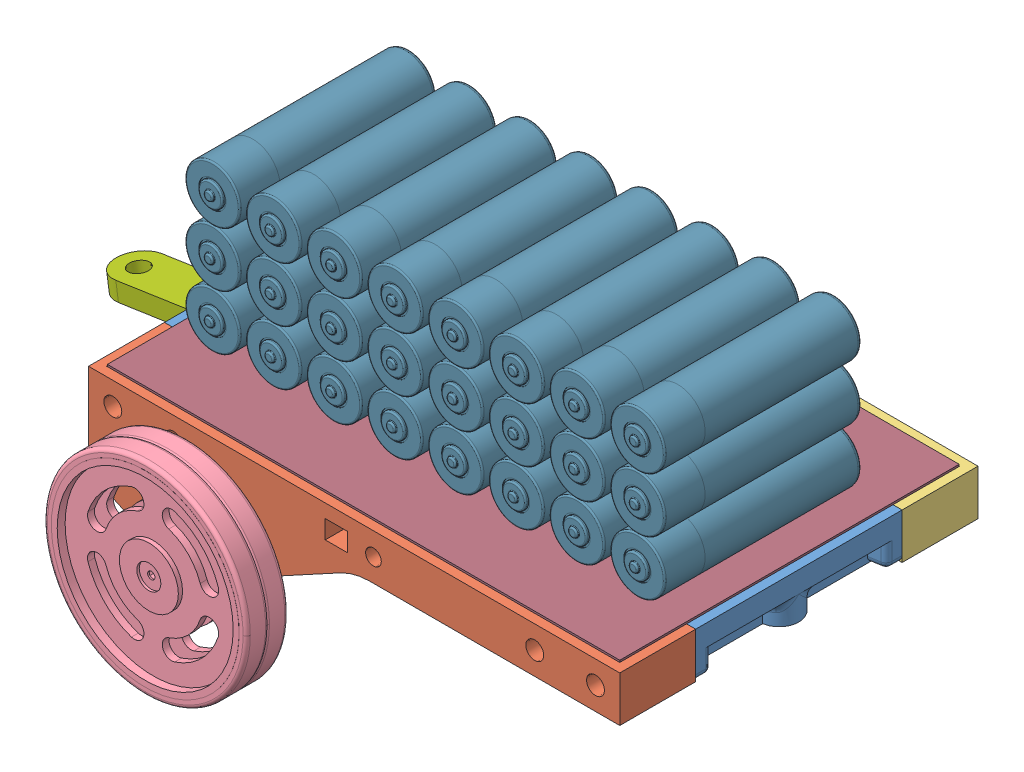
SolidWorks assembly WAGON2, TOP ASSY, configuration Default. Lengths in mm.
Overall size (226.29 129 145.66).
53 component instances, 14 part files, 63 mates.
Components (placement in the parent):
- WAGON2, CHASSIS, TOP-1: WAGON2, CHASSIS, TOP [Default] at (-93.9751 43.1083 20.3022) size (175 15 80.6)
- WAGON2, CHASSIS, SIDE, RIGHT-1: WAGON2, CHASSIS, SIDE, RIGHT [Default] at (-93.9751 38.1083 79.3022) size (175 44 25)
- WAGON2, CHASSIS, SIDE, RIGHT, MIRROR-2: WAGON2, CHASSIS, SIDE, RIGHT, MIRROR [Default] at (-93.9751 38.1083 -38.6978) size (175 44 25)
- WAGON2, WHEEl, GM8-1: WAGON2, WHEEl, GM8 [Default] at (-148.9751 8.1083 83.0868) x (0 0 1) z (-1 0 0) size (7.52 66.8 66.8)
- WAGON2, WHEEl, GM8-2: WAGON2, WHEEl, GM8 [Default] at (-148.9751 8.1083 -42.4824) x (0 0 -1) z (0.999196 -0.040101 0) size (7.52 66.8 66.8)
- WAGON2, REAR HITCH, PIVOT SHAFT, 3MM-1: WAGON2, REAR HITCH, PIVOT SHAFT, 3MM [Default] at (-174.9751 34.2083 20.3022) x (0 0 1) z (-0.598714 0.800963 0) size (28 3 3)
- SENSOR, FSR, INTERLINK 406-1: SENSOR, FSR, INTERLINK 406 [Default] at (-93.9751 44.3383 20.3022) x (0 0 1) z (-1 0 0) size (43.7 18.96 67.12)
- WAGON2, REAR HITCH, PIVOT ARM-1: WAGON2, REAR HITCH, PIVOT ARM [Default] at (-223.7399 22.2437 20.3022) x (0.988941 0.148309 0) z (0 0 1) size (63.2 15.2 15.2)
- SENSOR, BOM, VISHAY TSOP4838-1: SENSOR, BOM, VISHAY TSOP4838 [Default] at (-99.8171 38.1083 -30.6478) x (1 0 0) z (0 0 -1) size (9.49 6 5.4)
- SENSOR, BOM, VISHAY TSOP4838-2: SENSOR, BOM, VISHAY TSOP4838 [Default] at (-99.8171 38.1083 71.2522) size (9.49 6 5.4)
- SENSOR, BOM,TSAL6200-1: SENSOR, BOM,TSAL6200 [Default] at (-87.6251 38.1083 73.2022) x (0.945458 0.325744 0) z (0 0 1) size (5.39 5.8 14.08)
- SENSOR, BOM,TSAL6200-2: SENSOR, BOM,TSAL6200 [Default] at (-87.6251 38.1083 -32.5978) x (0.886273 -0.463163 0) z (0 0 -1) size (5.39 5.8 14.08)
- FASTENER, 4-40 THREAD FORMING, PHILIPS, 0'375IN, 93878A108-1: FASTENER, 4-40 THREAD FORMING, PHILIPS, 0'375IN, 93878A108 [93878A108] at (-173.4751 38.1083 59.3022) size (5.56 5.56 11.45)
- FASTENER, 4-40 THREAD FORMING, PHILIPS, 0'375IN, 93878A108-2: FASTENER, 4-40 THREAD FORMING, PHILIPS, 0'375IN, 93878A108 [93878A108] at (-153.4751 38.1083 59.3022) size (5.56 5.56 11.45)
- FASTENER, 4-40 THREAD FORMING, PHILIPS, 0'375IN, 93878A108-3: FASTENER, 4-40 THREAD FORMING, PHILIPS, 0'375IN, 93878A108 [93878A108] at (-34.4751 38.1083 59.3022) size (5.56 5.56 11.45)
- FASTENER, 4-40 THREAD FORMING, PHILIPS, 0'375IN, 93878A108-4: FASTENER, 4-40 THREAD FORMING, PHILIPS, 0'375IN, 93878A108 [93878A108] at (-14.4751 38.1083 59.3022) size (5.56 5.56 11.45)
- FASTENER, 4-40 THREAD FORMING, PHILIPS, 0'375IN, 93878A108-5: FASTENER, 4-40 THREAD FORMING, PHILIPS, 0'375IN, 93878A108 [93878A108] at (-153.4751 38.1083 -18.6978) x (-0.880957 -0.473196 0) z (0 0 -1) size (5.56 5.56 11.45)
- FASTENER, 4-40 THREAD FORMING, PHILIPS, 0'375IN, 93878A108-6: FASTENER, 4-40 THREAD FORMING, PHILIPS, 0'375IN, 93878A108 [93878A108] at (-173.4751 38.1083 -18.6978) x (-0.880957 -0.473196 0) z (0 0 -1) size (5.56 5.56 11.45)
- FASTENER, 4-40 THREAD FORMING, PHILIPS, 0'375IN, 93878A108-7: FASTENER, 4-40 THREAD FORMING, PHILIPS, 0'375IN, 93878A108 [93878A108] at (-34.4751 38.1083 -18.6978) x (-0.880957 -0.473196 0) z (0 0 -1) size (5.56 5.56 11.45)
- FASTENER, 4-40 THREAD FORMING, PHILIPS, 0'375IN, 93878A108-8: FASTENER, 4-40 THREAD FORMING, PHILIPS, 0'375IN, 93878A108 [93878A108] at (-14.4751 38.1083 -18.6978) x (-0.880957 -0.473196 0) z (0 0 -1) size (5.56 5.56 11.45)
- WAGON2, CHASSIS, PIVOT MOUNT-1: WAGON2, CHASSIS, PIVOT MOUNT [Default] at (-174.9751 31.6083 9.3022) size (13.34 2 6.5)
- WAGON2, CHASSIS, PIVOT MOUNT-2: WAGON2, CHASSIS, PIVOT MOUNT [Default] at (-174.9751 31.6083 31.3022) size (13.34 2 6.5)
- FASTENER, 4-40 THREAD FORMING, PHILIPS, 0'25IN, 93878A106-1: FASTENER, 4-40 THREAD FORMING, PHILIPS, 0'25IN, 93878A106 [93878A106] at (-171.7251 30.6083 31.3022) x (1 0 0) z (0 -1 0) size (5.56 5.56 8.28)
- FASTENER, 4-40 THREAD FORMING, PHILIPS, 0'25IN, 93878A106-2: FASTENER, 4-40 THREAD FORMING, PHILIPS, 0'25IN, 93878A106 [93878A106] at (-178.2251 30.6083 31.3022) x (1 0 0) z (0 -1 0) size (5.56 5.56 8.28)
- FASTENER, 4-40 THREAD FORMING, PHILIPS, 0'25IN, 93878A106-3: FASTENER, 4-40 THREAD FORMING, PHILIPS, 0'25IN, 93878A106 [93878A106] at (-171.7251 30.6083 9.3022) x (1 0 0) z (0 -1 0) size (5.56 5.56 8.28)
- FASTENER, 4-40 THREAD FORMING, PHILIPS, 0'25IN, 93878A106-4: FASTENER, 4-40 THREAD FORMING, PHILIPS, 0'25IN, 93878A106 [93878A106] at (-178.2251 30.6083 9.3022) x (1 0 0) z (0 -1 0) size (5.56 5.56 8.28)
- WAGON2, CHASSIS, TOP, LOAD PLATE-1: WAGON2, CHASSIS, TOP, LOAD PLATE [Default] at (-93.9751 44.5583 20.3022) size (168.8 1.59 111.8)
- WAGON2, WHEEl, GM8-3: WAGON2, WHEEl, GM8 [Default] at (-148.9751 8.1083 89.3987) x (0 0 1) z (-1 0 0) size (7.52 66.8 66.8)
- WAGON2, WHEEl, GM8-4: WAGON2, WHEEl, GM8 [Default] at (-148.9751 8.1083 -48.7943) x (0 0 -1) z (0.999196 -0.040101 0) size (7.52 66.8 66.8)
- BATTERY, UR18650E-1: BATTERY, UR18650E [Default] at (-164.6562 55.1708 -9.3854) x (0.958428 0.285334 0) z (0.285334 -0.958428 0) size (18.05 66.2 18.05)
- BATTERY, UR18650E-2: BATTERY, UR18650E [Default] at (-144.6562 55.1708 -9.3854) x (0.958428 0.285334 0) z (0.285334 -0.958428 0) size (18.05 66.2 18.05)
- BATTERY, UR18650E-3: BATTERY, UR18650E [Default] at (-124.6562 55.1708 -9.3854) x (0.958428 0.285334 0) z (0.285334 -0.958428 0) size (18.05 66.2 18.05)
- BATTERY, UR18650E-4: BATTERY, UR18650E [Default] at (-104.6562 55.1708 -9.3854) x (0.958428 0.285334 0) z (0.285334 -0.958428 0) size (18.05 66.2 18.05)
- BATTERY, UR18650E-5: BATTERY, UR18650E [Default] at (-84.6562 55.1708 -9.3854) x (0.958428 0.285334 0) z (0.285334 -0.958428 0) size (18.05 66.2 18.05)
- BATTERY, UR18650E-6: BATTERY, UR18650E [Default] at (-64.6562 55.1708 -9.3854) x (0.958428 0.285334 0) z (0.285334 -0.958428 0) size (18.05 66.2 18.05)
- BATTERY, UR18650E-7: BATTERY, UR18650E [Default] at (-44.6562 55.1708 -9.3854) x (0.958428 0.285334 0) z (0.285334 -0.958428 0) size (18.05 66.2 18.05)
- BATTERY, UR18650E-8: BATTERY, UR18650E [Default] at (-24.6562 55.1708 -9.3854) x (0.958428 0.285334 0) z (0.285334 -0.958428 0) size (18.05 66.2 18.05)
- BATTERY, UR18650E-9: BATTERY, UR18650E [Default] at (-164.6562 73.1708 -9.3854) x (0.958428 0.285334 0) z (0.285334 -0.958428 0) size (18.05 66.2 18.05)
- BATTERY, UR18650E-10: BATTERY, UR18650E [Default] at (-164.6562 91.1708 -9.3854) x (0.958428 0.285334 0) z (0.285334 -0.958428 0) size (18.05 66.2 18.05)
- BATTERY, UR18650E-11: BATTERY, UR18650E [Default] at (-144.6562 73.1708 -9.3854) x (0.958428 0.285334 0) z (0.285334 -0.958428 0) size (18.05 66.2 18.05)
- BATTERY, UR18650E-12: BATTERY, UR18650E [Default] at (-144.6562 91.1708 -9.3854) x (0.958428 0.285334 0) z (0.285334 -0.958428 0) size (18.05 66.2 18.05)
- BATTERY, UR18650E-13: BATTERY, UR18650E [Default] at (-124.6562 73.1708 -9.3854) x (0.958428 0.285334 0) z (0.285334 -0.958428 0) size (18.05 66.2 18.05)
- BATTERY, UR18650E-14: BATTERY, UR18650E [Default] at (-124.6562 91.1708 -9.3854) x (0.958428 0.285334 0) z (0.285334 -0.958428 0) size (18.05 66.2 18.05)
- BATTERY, UR18650E-15: BATTERY, UR18650E [Default] at (-104.6562 73.1708 -9.3854) x (0.958428 0.285334 0) z (0.285334 -0.958428 0) size (18.05 66.2 18.05)
- BATTERY, UR18650E-16: BATTERY, UR18650E [Default] at (-104.6562 91.1708 -9.3854) x (0.958428 0.285334 0) z (0.285334 -0.958428 0) size (18.05 66.2 18.05)
- BATTERY, UR18650E-17: BATTERY, UR18650E [Default] at (-84.6562 73.1708 -9.3854) x (0.958428 0.285334 0) z (0.285334 -0.958428 0) size (18.05 66.2 18.05)
- BATTERY, UR18650E-18: BATTERY, UR18650E [Default] at (-84.6562 91.1708 -9.3854) x (0.958428 0.285334 0) z (0.285334 -0.958428 0) size (18.05 66.2 18.05)
- BATTERY, UR18650E-19: BATTERY, UR18650E [Default] at (-64.6562 73.1708 -9.3854) x (0.958428 0.285334 0) z (0.285334 -0.958428 0) size (18.05 66.2 18.05)
- BATTERY, UR18650E-20: BATTERY, UR18650E [Default] at (-64.6562 91.1708 -9.3854) x (0.958428 0.285334 0) z (0.285334 -0.958428 0) size (18.05 66.2 18.05)
- BATTERY, UR18650E-21: BATTERY, UR18650E [Default] at (-44.6562 73.1708 -9.3854) x (0.958428 0.285334 0) z (0.285334 -0.958428 0) size (18.05 66.2 18.05)
- BATTERY, UR18650E-22: BATTERY, UR18650E [Default] at (-44.6562 91.1708 -9.3854) x (0.958428 0.285334 0) z (0.285334 -0.958428 0) size (18.05 66.2 18.05)
- BATTERY, UR18650E-23: BATTERY, UR18650E [Default] at (-24.6562 73.1708 -9.3854) x (0.958428 0.285334 0) z (0.285334 -0.958428 0) size (18.05 66.2 18.05)
- BATTERY, UR18650E-24: BATTERY, UR18650E [Default] at (-24.6562 91.1708 -9.3854) x (0.958428 0.285334 0) z (0.285334 -0.958428 0) size (18.05 66.2 18.05)
Mates (geometry in assembly coordinates):
- Coincident1: coincident anti-aligned: plane of WAGON2, CHASSIS, TOP-1 through (-181.4751 44.1083 54.3022) normal (0 0 1); plane of WAGON2, CHASSIS, SIDE, RIGHT-1 through (-6.4751 45.6083 54.3022) normal (0 0 -1)
- Coincident2: coincident aligned: plane of WAGON2, CHASSIS, TOP-1 through (-6.4751 44.1083 -13.6978) normal (0 1 0); plane of WAGON2, CHASSIS, SIDE, RIGHT-1 through (-9.4751 44.1083 76.3022) normal (0 1 0)
- Coincident3: coincident aligned: plane of WAGON2, CHASSIS, TOP-1 through (-93.9751 43.1083 20.3022) normal (1 0 0); plane of WAGON2, CHASSIS, SIDE, RIGHT-1 through (-93.9751 38.1083 79.3022) normal (1 0 0)
- Coincident6: coincident anti-aligned: plane of WAGON2, CHASSIS, SIDE, RIGHT-1 through (-6.4751 45.6083 79.3022) normal (0 0 1); plane of WAGON2, WHEEl, GM8-1 through (-144.0526 3.1858 79.3022) normal (0 0 -1)
- Concentric1: concentric aligned: cylinder of WAGON2, CHASSIS, SIDE, RIGHT-1 through (-148.9751 8.1083 78.3022) axis (0 0 1) radius 1.5; cylinder of WAGON2, WHEEl, GM8-1 through (-148.9751 8.1083 84.2933) axis (0 0 1) radius 1.2002
- Concentric2: concentric anti-aligned: cylinder of WAGON2, WHEEl, GM8-1 through (-148.9751 8.1083 85.6046) axis (0 0 -1) radius 33.401; cylinder of WAGON2, WHEEl, GM8-2 through (-148.9751 8.1083 -45.0001) axis (0 0 1) radius 33.401
- Coincident7: coincident anti-aligned: plane of WAGON2, CHASSIS, SIDE, RIGHT, MIRROR-2 through (-6.4751 45.6083 -38.6978) normal (0 0 -1); plane of WAGON2, WHEEl, GM8-2 through (-154.091 3.3872 -38.6978) normal (0 0 1)
- Concentric3: concentric anti-aligned: cylinder of WAGON2, CHASSIS, TOP-1 through (-174.9751 34.2083 28.0522) axis (0 0 1) radius 1.6; cylinder of WAGON2, REAR HITCH, PIVOT SHAFT, 3MM-1 through (-174.9751 34.2083 34.3022) axis (0 0 -1) radius 1.5
- Coincident8: coincident aligned: plane of WAGON2, CHASSIS, TOP-1 through (-93.9751 43.1083 20.3022) normal (0 0 1); plane of WAGON2, REAR HITCH, PIVOT SHAFT, 3MM-1
- Coincident9: coincident anti-aligned: plane of WAGON2, CHASSIS, TOP-1 through (-6.4751 44.1083 -13.6978) normal (0 1 0); plane of SENSOR, FSR, INTERLINK 406-1 through (-115.8251 44.1083 42.1522) normal (0 -1 0)
- Concentric4: concentric aligned: cylinder of WAGON2, REAR HITCH, PIVOT SHAFT, 3MM-1 through (-174.9751 34.2083 34.3022) axis (0 0 -1) radius 1.5; cylinder of WAGON2, REAR HITCH, PIVOT ARM-1 through (-174.9751 34.2083 27.9022) axis (0 0 -1) radius 1.6
- Width1: width anti-aligned: plane of WAGON2, REAR HITCH, PIVOT ARM-1 through (-194.22 27.6819 27.9022) normal (0 0 1); plane of WAGON2, REAR HITCH, PIVOT ARM-1 through (-223.8882 23.2327 12.7022) normal (0 0 -1); plane of WAGON2, CHASSIS, TOP-1 through (-174.9751 34.2083 28.0522) normal (0 0 -1); plane of WAGON2, CHASSIS, TOP-1 through (-174.9751 34.2083 12.5522) normal (0 0 1)
- Concentric5: concentric aligned: cylinder of WAGON2, CHASSIS, SIDE, RIGHT-1 through (-87.6251 38.1083 54.3022) axis (0 0 1) radius 2.59; cylinder of SENSOR, BOM,TSAL6200-1 through (-87.6251 38.1083 75.6922) axis (0 0 1) radius 2.49
- Width2: width anti-aligned: plane of WAGON2, CHASSIS, SIDE, RIGHT-1 through (-96.1341 41.1563 54.3022) normal (-1 0 0); plane of WAGON2, CHASSIS, SIDE, RIGHT-1 through (-103.5001 41.1563 54.3022) normal (1 0 0); plane of SENSOR, BOM, VISHAY TSOP4838-2 through (-96.3421 35.1083 73.2022) normal (1 0 0); plane of SENSOR, BOM, VISHAY TSOP4838-2 through (-103.2921 35.1083 73.2022) normal (-1 0 0)
- Width3: width anti-aligned: plane of WAGON2, CHASSIS, SIDE, RIGHT-1 through (-103.5001 41.1563 54.3022) normal (0 -1 0); plane of WAGON2, CHASSIS, SIDE, RIGHT-1 through (-103.5001 35.0603 54.3022) normal (0 1 0); plane of SENSOR, BOM, VISHAY TSOP4838-2 through (-103.2921 41.1083 73.2022) normal (0 1 0); plane of SENSOR, BOM, VISHAY TSOP4838-2 through (-103.2921 35.1083 73.2022) normal (0 -1 0)
- Coincident10: coincident aligned: plane of SENSOR, BOM, VISHAY TSOP4838-2 through (-96.3421 41.1083 73.2022) normal (0 0 1); circle of SENSOR, BOM,TSAL6200-1
- Coincident11: coincident aligned: plane of WAGON2, CHASSIS, SIDE, RIGHT-1 through (-6.4751 45.6083 69.3022) normal (0 0 -1); plane of SENSOR, BOM, VISHAY TSOP4838-2 through (-96.3421 41.1083 69.3022) normal (0 0 -1)
- Concentric6: concentric aligned: cylinder of WAGON2, CHASSIS, SIDE, RIGHT, MIRROR-2 through (-87.6251 38.1083 -13.6978) axis (0 0 -1) radius 2.59; cylinder of SENSOR, BOM,TSAL6200-2 through (-87.6251 38.1083 -35.0878) axis (0 0 -1) radius 2.49
- Width4: width anti-aligned: plane of SENSOR, BOM, VISHAY TSOP4838-1 through (-103.2921 41.1083 -32.5978) normal (0 1 0); plane of SENSOR, BOM, VISHAY TSOP4838-1 through (-103.2921 35.1083 -32.5978) normal (0 -1 0); plane of WAGON2, CHASSIS, SIDE, RIGHT, MIRROR-2 through (-103.5001 41.1563 -13.6978) normal (0 -1 0); plane of WAGON2, CHASSIS, SIDE, RIGHT, MIRROR-2 through (-103.5001 35.0603 -13.6978) normal (0 1 0)
- Width5: width anti-aligned: plane of SENSOR, BOM, VISHAY TSOP4838-1 through (-103.2921 41.1083 -32.5978) normal (-1 0 0); plane of SENSOR, BOM, VISHAY TSOP4838-1 through (-96.3421 41.1083 -32.5978) normal (1 0 0); plane of WAGON2, CHASSIS, SIDE, RIGHT, MIRROR-2 through (-103.5001 41.1563 -13.6978) normal (1 0 0); plane of WAGON2, CHASSIS, SIDE, RIGHT, MIRROR-2 through (-96.1341 41.1563 -13.6978) normal (-1 0 0)
- Coincident12: coincident aligned: plane of SENSOR, BOM, VISHAY TSOP4838-1 through (-96.3421 35.1083 -32.5978) normal (0 0 -1); circle of SENSOR, BOM,TSAL6200-2
- Coincident13: coincident aligned: plane of WAGON2, CHASSIS, SIDE, RIGHT, MIRROR-2 through (-6.4751 45.6083 -28.6978) normal (0 0 1); plane of SENSOR, BOM, VISHAY TSOP4838-1 through (-96.3421 35.1083 -28.6978) normal (0 0 1)
- Coincident14: coincident aligned: plane of WAGON2, CHASSIS, TOP-1 through (-93.9751 43.1083 20.3022) normal (0 0 1); plane of SENSOR, FSR, INTERLINK 406-1 through (-93.9751 44.3383 20.3022) normal (0 0 1)
- Coincident15: coincident anti-aligned: plane of WAGON2, CHASSIS, TOP-1 through (-93.9751 43.1083 20.3022) normal (1 0 0); plane of SENSOR, FSR, INTERLINK 406-1 through (-93.9751 44.3383 20.3022) normal (-1 0 0)
- Concentric7: concentric anti-aligned: cylinder of WAGON2, CHASSIS, SIDE, RIGHT-1 through (-173.4751 38.1083 45.9584) axis (0 0 1) radius 2.95; circle of FASTENER, 4-40 THREAD FORMING, PHILIPS, 0'375IN, 93878A108-1
- Concentric8: concentric anti-aligned: cylinder of WAGON2, CHASSIS, SIDE, RIGHT-1 through (-153.4751 38.1083 45.9584) axis (0 0 1) radius 2.95; circle of FASTENER, 4-40 THREAD FORMING, PHILIPS, 0'375IN, 93878A108-2
- Concentric9: concentric anti-aligned: cylinder of WAGON2, CHASSIS, SIDE, RIGHT-1 through (-34.4751 38.1083 45.9584) axis (0 0 1) radius 2.95; circle of FASTENER, 4-40 THREAD FORMING, PHILIPS, 0'375IN, 93878A108-3
- Concentric10: concentric anti-aligned: cylinder of WAGON2, CHASSIS, SIDE, RIGHT-1 through (-14.4751 38.1083 45.9584) axis (0 0 1) radius 2.95; circle of FASTENER, 4-40 THREAD FORMING, PHILIPS, 0'375IN, 93878A108-4
- Coincident16: coincident aligned: plane of FASTENER, 4-40 THREAD FORMING, PHILIPS, 0'375IN, 93878A108-3 through (-34.4751 38.1083 59.3022) normal (0 0 -1); plane of FASTENER, 4-40 THREAD FORMING, PHILIPS, 0'375IN, 93878A108-4 through (-14.4751 38.1083 59.3022) normal (0 0 -1)
- Coincident17: coincident aligned: plane of FASTENER, 4-40 THREAD FORMING, PHILIPS, 0'375IN, 93878A108-2 through (-153.4751 38.1083 59.3022) normal (0 0 -1); plane of FASTENER, 4-40 THREAD FORMING, PHILIPS, 0'375IN, 93878A108-3 through (-34.4751 38.1083 59.3022) normal (0 0 -1)
- Coincident18: coincident aligned: plane of FASTENER, 4-40 THREAD FORMING, PHILIPS, 0'375IN, 93878A108-1 through (-173.4751 38.1083 59.3022) normal (0 0 -1); plane of FASTENER, 4-40 THREAD FORMING, PHILIPS, 0'375IN, 93878A108-2 through (-153.4751 38.1083 59.3022) normal (0 0 -1)
- Coincident19: coincident anti-aligned: plane of WAGON2, CHASSIS, SIDE, RIGHT-1 through (-6.4751 45.6083 59.3022) normal (0 0 1); plane of FASTENER, 4-40 THREAD FORMING, PHILIPS, 0'375IN, 93878A108-1 through (-173.4751 38.1083 59.3022) normal (0 0 -1)
- Concentric11: concentric anti-aligned: cylinder of WAGON2, CHASSIS, SIDE, RIGHT, MIRROR-2 through (-14.4751 38.1083 -5.3539) axis (0 0 -1) radius 2.95; circle of FASTENER, 4-40 THREAD FORMING, PHILIPS, 0'375IN, 93878A108-8
- Concentric12: concentric anti-aligned: cylinder of WAGON2, CHASSIS, SIDE, RIGHT, MIRROR-2 through (-34.4751 38.1083 -5.3539) axis (0 0 -1) radius 2.95; circle of FASTENER, 4-40 THREAD FORMING, PHILIPS, 0'375IN, 93878A108-7
- Concentric13: concentric anti-aligned: cylinder of WAGON2, CHASSIS, SIDE, RIGHT, MIRROR-2 through (-173.4751 38.1083 -5.3539) axis (0 0 -1) radius 2.95; circle of FASTENER, 4-40 THREAD FORMING, PHILIPS, 0'375IN, 93878A108-6
- Concentric14: concentric anti-aligned: cylinder of WAGON2, CHASSIS, SIDE, RIGHT, MIRROR-2 through (-153.4751 38.1083 -5.3539) axis (0 0 -1) radius 2.95; circle of FASTENER, 4-40 THREAD FORMING, PHILIPS, 0'375IN, 93878A108-5
- Coincident20: coincident aligned: plane of FASTENER, 4-40 THREAD FORMING, PHILIPS, 0'375IN, 93878A108-5 through (-153.4751 38.1083 -18.6978) normal (0 0 1); plane of FASTENER, 4-40 THREAD FORMING, PHILIPS, 0'375IN, 93878A108-6 through (-173.4751 38.1083 -18.6978) normal (0 0 1)
- Coincident21: coincident aligned: plane of FASTENER, 4-40 THREAD FORMING, PHILIPS, 0'375IN, 93878A108-5 through (-153.4751 38.1083 -18.6978) normal (0 0 1); plane of FASTENER, 4-40 THREAD FORMING, PHILIPS, 0'375IN, 93878A108-7 through (-34.4751 38.1083 -18.6978) normal (0 0 1)
- Coincident22: coincident aligned: plane of FASTENER, 4-40 THREAD FORMING, PHILIPS, 0'375IN, 93878A108-7 through (-34.4751 38.1083 -18.6978) normal (0 0 1); plane of FASTENER, 4-40 THREAD FORMING, PHILIPS, 0'375IN, 93878A108-8 through (-14.4751 38.1083 -18.6978) normal (0 0 1)
- Coincident23: coincident anti-aligned: plane of WAGON2, CHASSIS, SIDE, RIGHT, MIRROR-2 through (-6.4751 45.6083 -18.6978) normal (0 0 -1); plane of FASTENER, 4-40 THREAD FORMING, PHILIPS, 0'375IN, 93878A108-8 through (-14.4751 38.1083 -18.6978) normal (0 0 1)
- Concentric15: concentric aligned: cylinder of WAGON2, CHASSIS, TOP-1 through (-178.2251 37.6083 9.3022) axis (0 -1 0) radius 1.25; cylinder of WAGON2, CHASSIS, PIVOT MOUNT-1 through (-178.2251 32.6083 9.3022) axis (0 -1 0) radius 1.7
- Concentric16: concentric aligned: cylinder of WAGON2, CHASSIS, TOP-1 through (-171.7251 37.6083 9.3022) axis (0 -1 0) radius 1.25; cylinder of WAGON2, CHASSIS, PIVOT MOUNT-1 through (-171.7251 32.6083 9.3022) axis (0 -1 0) radius 1.7
- Coincident24: coincident anti-aligned: plane of WAGON2, CHASSIS, TOP-1 through (-173.3751 32.6083 12.5522) normal (0 -1 0); plane of WAGON2, CHASSIS, PIVOT MOUNT-1 through (-168.3051 32.6083 12.5522) normal (0 1 0)
- Coincident25: coincident anti-aligned: plane of WAGON2, CHASSIS, TOP-1 through (-176.5751 32.6083 28.0522) normal (0 -1 0); plane of WAGON2, CHASSIS, PIVOT MOUNT-2 through (-168.3051 32.6083 34.5522) normal (0 1 0)
- Concentric17: concentric aligned: cylinder of WAGON2, CHASSIS, TOP-1 through (-171.7251 37.6083 31.3022) axis (0 -1 0) radius 1.25; cylinder of WAGON2, CHASSIS, PIVOT MOUNT-2 through (-171.7251 32.6083 31.3022) axis (0 -1 0) radius 1.7
- Concentric18: concentric aligned: cylinder of WAGON2, CHASSIS, TOP-1 through (-178.2251 37.6083 31.3022) axis (0 -1 0) radius 1.25; cylinder of WAGON2, CHASSIS, PIVOT MOUNT-2 through (-178.2251 32.6083 31.3022) axis (0 -1 0) radius 1.7
- Concentric19: concentric anti-aligned: cylinder of WAGON2, CHASSIS, PIVOT MOUNT-2 through (-171.7251 32.6083 31.3022) axis (0 -1 0) radius 1.7; circle of FASTENER, 4-40 THREAD FORMING, PHILIPS, 0'25IN, 93878A106-1
- Concentric20: concentric anti-aligned: cylinder of WAGON2, CHASSIS, PIVOT MOUNT-2 through (-178.2251 32.6083 31.3022) axis (0 -1 0) radius 1.7; circle of FASTENER, 4-40 THREAD FORMING, PHILIPS, 0'25IN, 93878A106-2
- Coincident27: coincident aligned: plane of FASTENER, 4-40 THREAD FORMING, PHILIPS, 0'25IN, 93878A106-1 through (-171.7251 30.6083 31.3022) normal (0 1 0); plane of FASTENER, 4-40 THREAD FORMING, PHILIPS, 0'25IN, 93878A106-2 through (-178.2251 30.6083 31.3022) normal (0 1 0)
- Coincident28: coincident anti-aligned: plane of WAGON2, CHASSIS, PIVOT MOUNT-2 through (-168.3051 30.6083 34.5522) normal (0 -1 0); plane of FASTENER, 4-40 THREAD FORMING, PHILIPS, 0'25IN, 93878A106-2 through (-178.2251 30.6083 31.3022) normal (0 1 0)
- Coincident29: coincident aligned: plane of FASTENER, 4-40 THREAD FORMING, PHILIPS, 0'25IN, 93878A106-3 through (-171.7251 30.6083 9.3022) normal (0 1 0); plane of FASTENER, 4-40 THREAD FORMING, PHILIPS, 0'25IN, 93878A106-4 through (-178.2251 30.6083 9.3022) normal (0 1 0)
- Concentric21: concentric anti-aligned: cylinder of WAGON2, CHASSIS, PIVOT MOUNT-1 through (-171.7251 32.6083 9.3022) axis (0 -1 0) radius 1.7; circle of FASTENER, 4-40 THREAD FORMING, PHILIPS, 0'25IN, 93878A106-3
- Concentric22: concentric anti-aligned: cylinder of WAGON2, CHASSIS, PIVOT MOUNT-1 through (-178.2251 32.6083 9.3022) axis (0 -1 0) radius 1.7; circle of FASTENER, 4-40 THREAD FORMING, PHILIPS, 0'25IN, 93878A106-4
- Coincident30: coincident anti-aligned: plane of WAGON2, CHASSIS, PIVOT MOUNT-1 through (-168.3051 30.6083 12.5522) normal (0 -1 0); plane of FASTENER, 4-40 THREAD FORMING, PHILIPS, 0'25IN, 93878A106-4 through (-178.2251 30.6083 9.3022) normal (0 1 0)
- Coincident31: coincident anti-aligned: plane of SENSOR, FSR, INTERLINK 406-1 through (-74.9251 44.5583 39.3522) normal (0 1 0); plane of WAGON2, CHASSIS, TOP, LOAD PLATE-1 through (-9.5751 44.5583 76.2022) normal (0 -1 0)
- Coincident32: coincident aligned: plane of WAGON2, CHASSIS, TOP-1 through (-93.9751 43.1083 20.3022) normal (1 0 0); plane of WAGON2, CHASSIS, TOP, LOAD PLATE-1 through (-93.9751 44.5583 20.3022) normal (1 0 0)
- Coincident33: coincident aligned: plane of WAGON2, CHASSIS, TOP-1 through (-93.9751 43.1083 20.3022) normal (0 0 1); plane of WAGON2, CHASSIS, TOP, LOAD PLATE-1 through (-93.9751 44.5583 20.3022) normal (0 0 1)
- Coincident34: coincident anti-aligned: plane of WAGON2, WHEEl, GM8-1 through (-158.8072 -1.7238 85.6141) normal (0 0 1); plane of WAGON2, WHEEl, GM8-3 through (-144.0526 3.1858 85.6141) normal (0 0 -1)
- Concentric23: concentric aligned: cylinder of WAGON2, WHEEl, GM8-1 through (-148.9751 8.1083 85.6046) axis (0 0 -1) radius 33.401; cylinder of WAGON2, WHEEl, GM8-3 through (-148.9751 8.1083 91.9165) axis (0 0 -1) radius 33.401
- Coincident35: coincident anti-aligned: plane of WAGON2, WHEEl, GM8-2 through (-139.5452 -2.1101 -45.0097) normal (0 0 -1); plane of WAGON2, WHEEl, GM8-4 through (-154.091 3.3872 -45.0097) normal (0 0 1)
- Concentric24: concentric aligned: cylinder of WAGON2, WHEEl, GM8-2 through (-148.9751 8.1083 -45.0001) axis (0 0 1) radius 33.401; cylinder of WAGON2, WHEEl, GM8-4 through (-148.9751 8.1083 -51.312) axis (0 0 1) radius 33.401
- Tangent1: tangent anti-aligned: plane of WAGON2, CHASSIS, TOP, LOAD PLATE-1 through (-9.5751 46.1458 76.2022) normal (0 1 0); cylinder of BATTERY, UR18650E-1 through (-164.6562 55.1708 55.3146) axis (0 0 -1) radius 9.025
- Parallel1: parallel aligned: plane of WAGON2, CHASSIS, SIDE, RIGHT-1 through (-6.4751 45.6083 79.3022) normal (0 0 1); plane of BATTERY, UR18650E-1 through (-164.6562 55.1708 55.3146) normal (0 0 1)
